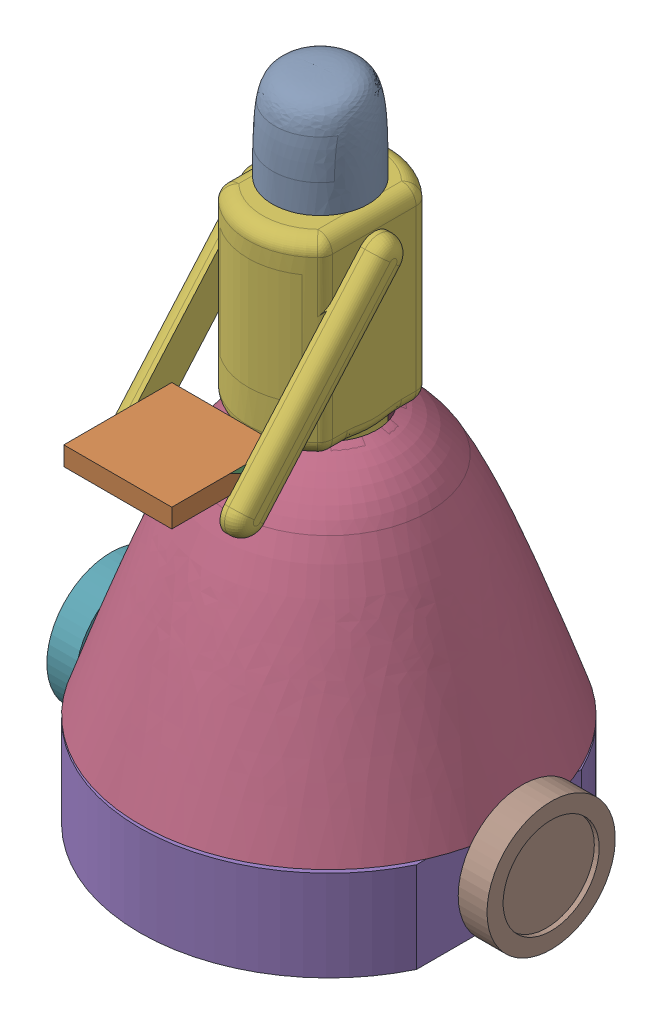
SolidWorks assembly Assem1, configuration Default. Lengths in mm.
Overall size (230.57 346.37 207.82).
9 component instances, 6 part files, 0 mates.
Components (placement in the parent):
- head_V1-1: head_V1 [Default] at (-3.7404 292.4519 1.9995) x (-0.996917 0 0.078459) z (-0.078459 0 -0.996917) size (50.8 50 50.8)
- plate_V1-2: plate_V1 [Default] at (-3.8587 198.6543 80.4962) size (57.15 10 57.15)
- Pololu-Wheel-32x7mm-1: Pololu-Wheel-32x7mm [По умолчанию] at (-116.5937 1.1515 -27.5589) (suppressed, hidden)
- Pololu-Wheel-32x7mm-2: Pololu-Wheel-32x7mm [По умолчанию] at (73.3106 1.1515 -27.5589) (suppressed, hidden)
- Upper_V1-3: Upper_V1 [Default] at (0.5086 47.5147 1.7706) size (200 144.32 200)
- Base_V1-4: Base_V1 [Default] at (0 -2.6412 1.2483) size (180.09 48 200)
- Mid_V1-2: Mid_V1 [Default] at (-4.1082 189.4386 1.7312) size (77.15 125.4 119.69)
- Wheel-1: Wheel [Default] at (-115.3959 30.0355 1.1331) x (0 -1 0) z (0 0 1) size (67.87 25.4 67.87)
- Wheel-2: Wheel [Default] at (115.1694 30.0142 -1.1891) x (0 1 0) z (0 0 1) size (67.87 25.4 67.87)
